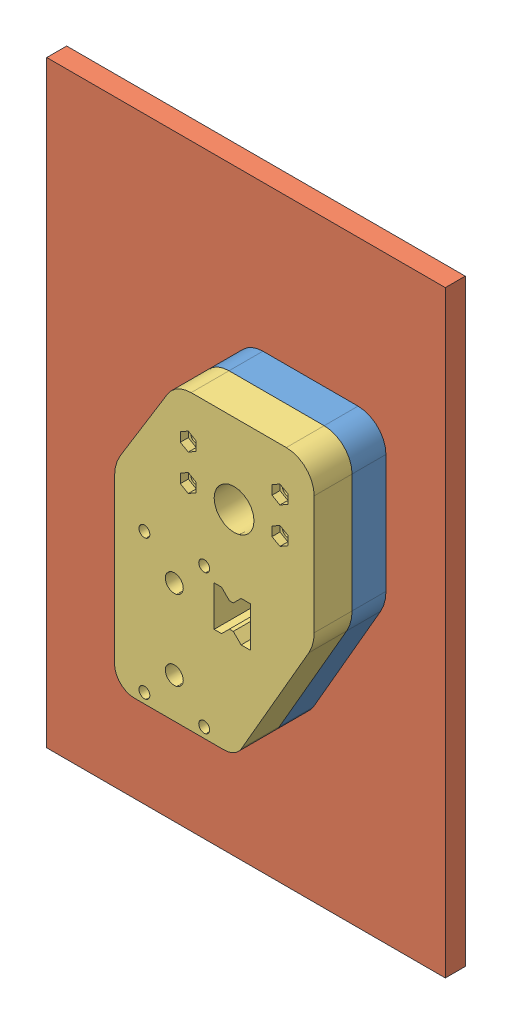
SolidWorks assembly 4, configuration Default. Lengths in mm.
Overall size (200 300 27).
3 component instances, 3 part files, 6 mates.
Components (placement in the parent):
- Y Screw Support motor top end right-1: Y Screw Support motor top end right [Default] at (-10 -390.3941 27) x (-1 0 0) z (0 0 -1) size (100.2 147 19)
- platform-1: platform [Default] at origin size (200 300 10)
- Y Screw Support motor top end left2-1: Y Screw Support motor top end left2 [Default] at (-10 -390.3941 46) x (-1 0 0) z (0 0 -1) size (100.2 147 19) (hidden)
Mates (geometry in assembly coordinates):
- Coincident7: coincident anti-aligned: plane of Y Screw Support motor top end right-1; line of platform-1 through (32.4795 143.11 8) axis (0.5 -0.866025 0)
- Concentric3: concentric: cylinder of Y Screw Support motor top end right-1 through (100 139.6059 8) axis (0 0 1) radius 4.5; cylinder of platform-1 through (100 139.6059 0) axis (0 0 1) radius 4.45
- Concentric4: concentric: cylinder of Y Screw Support motor top end right-1 through (100 99.6059 8) axis (0 0 1) radius 4.5; cylinder of platform-1 through (100 99.6059 0) axis (0 0 1) radius 4.45
- Coincident13: coincident: plane of platform-1 through (108.464 212.6059 8) normal (0 0 1); plane of Y Screw Support motor top end right-1 through (83 82.6059 8) normal (0 0 -1)
- Concentric5: concentric aligned: cylinder of Y Screw Support motor top end right-1 through (100 139.6059 8) axis (0 0 -1) radius 4.5; cylinder of Y Screw Support motor top end left2-1 through (100 139.6059 27) axis (0 0 -1) radius 4.5
- Concentric6: concentric aligned: cylinder of Y Screw Support motor top end right-1 through (100 99.6059 8) axis (0 0 -1) radius 4.5; cylinder of Y Screw Support motor top end left2-1 through (100 99.6059 27) axis (0 0 -1) radius 4.5
